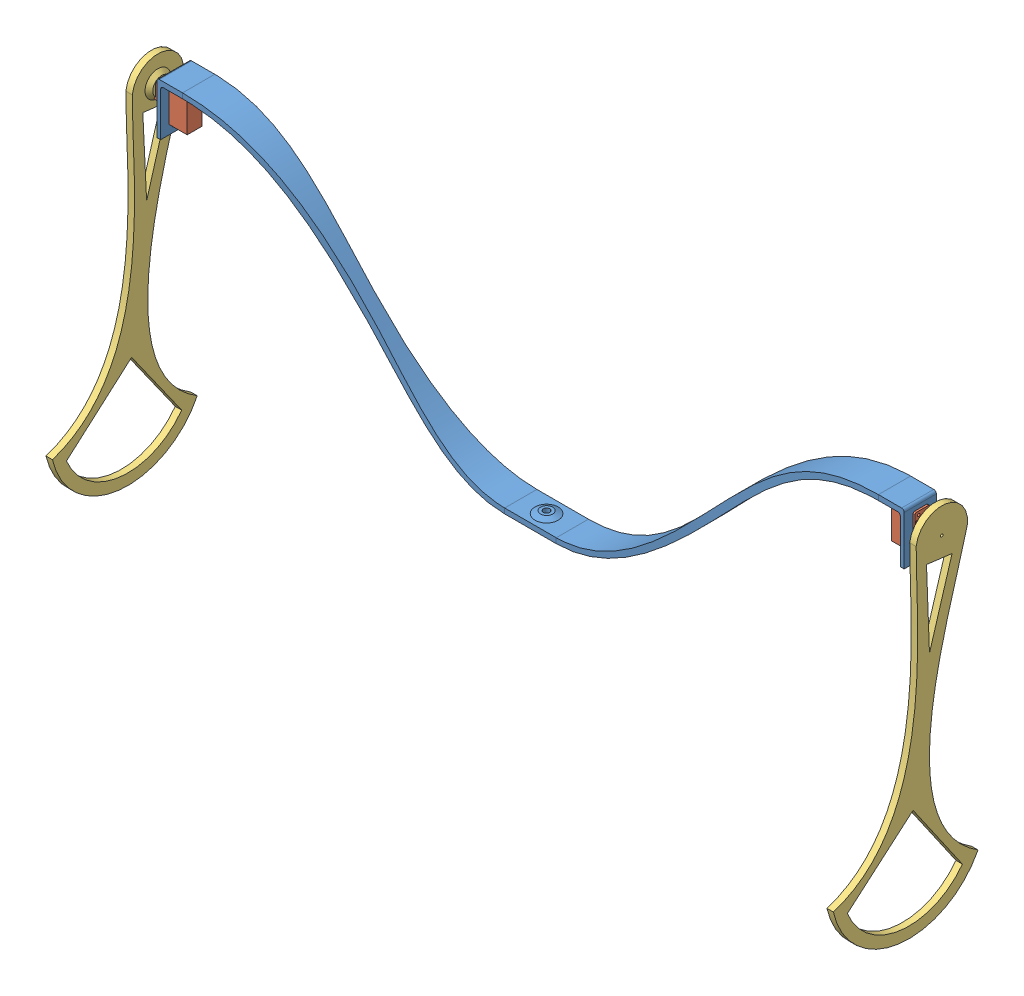
SolidWorks assembly robot2_assemblage, configuration Défaut. Lengths in mm.
Overall size (612.88 292.11 147.82).
5 component instances, 3 part files, 10 mates.
Components (placement in the parent):
- robot2_bras-1: robot2_bras [Défaut] at (-32.9679 -49.9571 -12.5) size (580 158 25)
- servo2-1: servo2 [Défaut] at (-322.9679 71.0429 -5.5) x (0 0 1) z (-1 0 0) size (11.43 32.26 30.46)
- servo2-2: servo2 [Défaut] at (257.0321 71.0429 5.5) x (0 0 -1) z (1 0 0) size (11.43 32.26 30.46)
- robot2_pied-1: robot2_pied [Défaut] at (268.4701 88.4419 -0.215) x (1 0 0) z (0 0.127137 0.991885) size (8 280 113.14)
- robot2_pied-2: robot2_pied [Défaut] at (-334.4059 88.4419 0.215) x (-1 0 0) z (0 -0.116507 -0.99319) size (8 280 113.14)
Mates (geometry in assembly coordinates):
- Coïncidente1: coincident anti-aligned: plane of robot2_bras-1 through (-310.9679 94.0429 -5.5) normal (0 0 1); plane of servo2-1 through (-322.9679 71.0429 -5.5) normal (0 0 -1)
- Coïncidente2: coincident anti-aligned: plane of robot2_bras-1 through (-310.9679 71.0429 5.5) normal (0 1 0); plane of servo2-1 through (-322.9679 71.0429 5.93) normal (0 -1 0)
- Coïncidente3: coincident anti-aligned: plane of robot2_bras-1 through (-322.9679 104.0429 12.5) normal (-1 0 0); plane of servo2-1 through (-322.9679 94.4109 5.93) normal (1 0 0)
- Coïncidente4: coincident anti-aligned: plane of robot2_bras-1 through (245.0321 94.0429 5.5) normal (0 0 -1); plane of servo2-2 through (257.0321 71.0429 5.5) normal (0 0 1)
- Coïncidente5: coincident anti-aligned: plane of robot2_bras-1 through (245.0321 71.0429 5.5) normal (0 1 0); plane of servo2-2 through (257.0321 71.0429 -5.93) normal (0 -1 0)
- Coïncidente6: coincident anti-aligned: plane of robot2_bras-1 through (257.0321 104.0429 12.5) normal (1 0 0); plane of servo2-2 through (257.0321 66.5979 -5.93) normal (-1 0 0)
- Coïncidente7: coincident anti-aligned: plane of servo2-2 through (270.4701 88.4419 -2.715) normal (1 0 0); plane of robot2_pied-1 through (270.4701 88.4419 -0.215) normal (-1 0 0)
- Coaxiale1: concentric aligned: circle of servo2-2; circle of robot2_pied-1
- Coaxiale3: concentric aligned: circle of servo2-1; circle of robot2_pied-2
- Coïncidente9: coincident anti-aligned: plane of servo2-1 through (-336.4059 88.4419 2.715) normal (-1 0 0); plane of robot2_pied-2 through (-336.4059 88.4419 0.215) normal (1 0 0)
